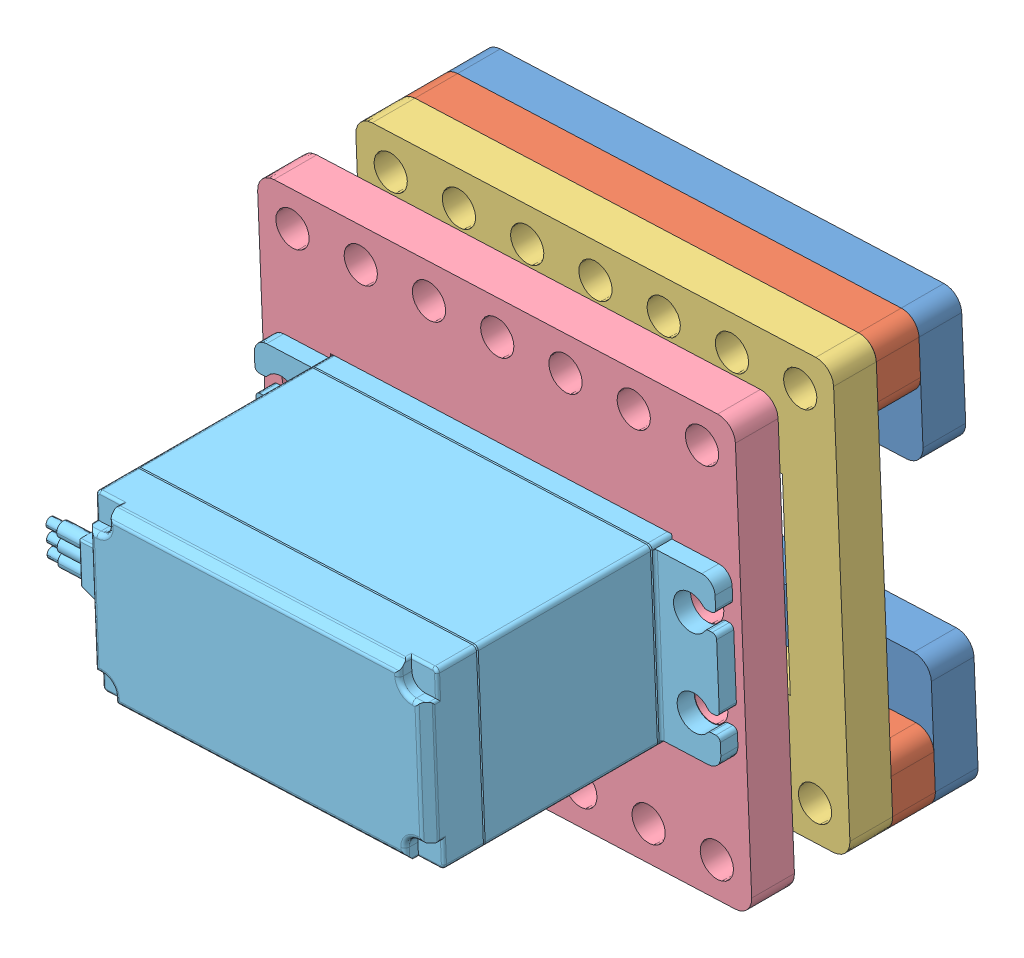
SolidWorks assembly assensceur fou9a, configuration Default. Lengths in mm.
Overall size (58.03 51.54 55.5).
10 component instances, 8 part files, 27 mates.
Components (placement in the parent):
- 3mm support servo 5-1: 3mm support servo 5 [Default] at (55.3297 16.1146 111.995) x (-0.99911 -0.042175 0) z (0.042175 -0.99911 0) size (56 5 15)
- support servo 2-1: support servo 2 [Default] at (111.2799 18.4764 116.995) x (-0.99911 -0.042175 0) z (0.042175 -0.99911 0) size (56 5 8)
- X7 support servo 3-1: X7 support servo 3 [Default] at (55.3297 16.1146 121.995) x (-0.99911 -0.042175 0) z (0.042175 -0.99911 0) size (56 5 49.22)
- support servo 4-1: support servo 4 [Default] at (35.4252 -33.9894 133.495) x (0.99911 0.042175 0) z (-0.042175 0.99911 0) size (56 5 49.22)
- MG995.step-1: MG995.step [Default] at (84.3427 -7.2923 162.495) x (-0.99911 -0.042175 0) z (0 0 -1) size (55.5 20 44.5)
- 3mm support servo 5-2: 3mm support servo 5 [Default] at (57.4056 -33.0616 106.995) x (-0.99911 -0.042175 0) z (-0.042175 0.99911 0) size (56 5 15)
- new attach-1: new attach [Default] at (74.3516 -7.7141 116.995) x (0.99087 -0.134821 0) z (0 0 1) size (21 21 5.5)
- NEW ATTACH V4-1: NEW ATTACH V4 [Default] at (74.3516 -7.7141 111.995) x (-0.134821 -0.99087 0) z (0 0 1) size (24.86 25 5)
- support servo 2-3: support servo 2 [Default] at (57.4056 -33.0616 116.995) x (0.99911 0.042175 0) z (-0.042175 0.99911 0) size (56 5 8)
- NEW HORN-1: NEW HORN [Default] at (84.3427 -7.2923 117.995) x (-0.99911 -0.042175 0) z (0 0 -1) size (9.55 9.02 10)
Mates (geometry in assembly coordinates):
- Concentric2: concentric anti-aligned: cylinder of support servo 4-1 through (60.575 -13.3001 133.495) axis (0 0 -1) radius 1.95; cylinder of MG995.step-1 through (60.575 -13.3001 133.495) axis (0 0 1) radius 2
- Coincident3: coincident anti-aligned: plane of support servo 4-1 through (131.3465 17.3217 133.495) normal (0 0 1); plane of MG995.step-1 through (84.3427 -7.2923 133.495) normal (0 0 -1)
- Concentric12: concentric aligned: cylinder of MG995.step-1 through (74.3516 -7.7141 122.995) axis (0 0 1) radius 2; cylinder of new attach-1 through (74.3516 -7.7141 117.995) axis (0 0 1) radius 2.75
- Coincident30: coincident anti-aligned: plane of MG995.step-1 through (74.3516 -7.7141 117.995) normal (0 0 -1); plane of new attach-1 through (74.3516 -7.7141 117.995) normal (0 0 1)
- Concentric13: concentric aligned: cylinder of new attach-1 through (74.3516 -7.7141 120.495) axis (0 0 -1) radius 1.6; cylinder of NEW ATTACH V4-1 through (74.3516 -7.7141 116.995) axis (0 0 -1) radius 1.6
- Coincident34: coincident anti-aligned: plane of new attach-1 through (74.3516 -7.7141 116.995) normal (0 0 -1); plane of NEW ATTACH V4-1 through (74.3516 -7.7141 116.995) normal (0 0 1)
- Concentric15: concentric: cylinder of new attach-1 through (82.0211 -6.2346 115.495) axis (0 0 1) radius 1; cylinder of new attach 2-1 through (82.0211 -6.2346 116.995) axis (0 0 -1) radius 1
- Coincident44: coincident aligned: plane of support servo 4-1 through (113.3558 -30.6998 138.495) normal (0.99911 0.042175 0); plane of support servo 2-3 through (113.2714 -28.7015 111.995) normal (0.99911 0.042175 0)
- Coincident45: coincident aligned: plane of support servo 2-1 through (111.3643 16.4782 111.995) normal (0.99911 0.042175 0); plane of support servo 4-1 through (113.3558 -30.6998 138.495) normal (0.99911 0.042175 0)
- Coincident46: coincident aligned: plane of support servo 2-1 through (111.3643 16.4782 111.995) normal (0.99911 0.042175 0); plane of support servo 3-1 through (111.3643 16.4782 116.995) normal (0.99911 0.042175 0)
- Coincident48: coincident anti-aligned: plane of support servo 2-1 through (57.581 10.2043 116.995) normal (0 0 1); plane of support servo 3-1 through (59.3194 -30.979 116.995) normal (0 0 -1)
- Coincident49: coincident aligned: plane of support servo 2-1 through (109.2817 18.3921 111.995) normal (-0.042175 0.99911 0); plane of support servo 3-1 through (109.2817 18.3921 116.995) normal (-0.042175 0.99911 0)
- Coincident50: coincident anti-aligned: plane of support servo 4-1 through (63.9388 1.855 133.495) normal (0.042175 -0.99911 0); plane of MG995.step-1 through (103.9032 3.5423 126.495) normal (-0.042175 0.99911 0)
- Coincident51: coincident anti-aligned: plane of 3mm support servo 5-1 through (57.8762 3.2106 111.995) normal (0 0 1); plane of support servo 2-1 through (57.581 10.2043 111.995) normal (0 0 -1)
- Coincident52: coincident aligned: plane of 3mm support servo 5-1 through (109.2817 18.3921 106.995) normal (-0.042175 0.99911 0); plane of support servo 2-1 through (109.2817 18.3921 111.995) normal (-0.042175 0.99911 0)
- Coincident53: coincident aligned: plane of 3mm support servo 5-1 through (55.4141 14.1164 106.995) normal (-0.99911 -0.042175 0); plane of support servo 2-1 through (55.4141 14.1164 111.995) normal (-0.99911 -0.042175 0)
- Coincident54: coincident anti-aligned: plane of 3mm support servo 5-2 through (58.8555 -19.9888 111.995) normal (0 0 1); plane of support servo 2-3 through (111.1045 -24.7895 111.995) normal (0 0 -1)
- Coincident55: coincident aligned: plane of 3mm support servo 5-2 through (111.3575 -30.7841 111.995) normal (0.042175 -0.99911 0); plane of support servo 2-3 through (59.4038 -32.9772 111.995) normal (0.042175 -0.99911 0)
- Coincident56: coincident aligned: plane of 3mm support servo 5-2 through (57.3212 -31.0633 111.995) normal (-0.99911 -0.042175 0); plane of support servo 2-3 through (57.3212 -31.0633 111.995) normal (-0.99911 -0.042175 0)
- Coincident57: coincident aligned: plane of NEW ATTACH V4-1 through (74.3516 -7.7141 111.995) normal (0 0 -1); plane of support servo 2-3 through (111.1045 -24.7895 111.995) normal (0 0 -1)
- Coincident58: coincident anti-aligned: plane of support servo 3-1 through (59.3194 -30.979 116.995) normal (0 0 -1); plane of support servo 2-3 through (111.1045 -24.7895 116.995) normal (0 0 1)
- Coincident59: coincident aligned: plane of support servo 3-1 through (111.3575 -30.7841 116.995) normal (0.042175 -0.99911 0); plane of support servo 2-3 through (59.4038 -32.9772 111.995) normal (0.042175 -0.99911 0)
- Coincident60: coincident aligned: plane of support servo 4-1 through (37.4234 -33.9051 128.495) normal (0.042175 -0.99911 0); plane of support servo 2-3 through (59.4038 -32.9772 111.995) normal (0.042175 -0.99911 0)
- InPlace1: in place: plane of MG995.step-1 through (74.3516 -7.7141 117.995) normal (0 0 -1); plane of ? through (0 0 117.995) normal (0 0 -1); moOrthogonalPlaneRef_w of MG995.step-1 through (74.3516 -7.7141 117.995) normal (0 0 -1); plane of ? through (0 0 117.995) normal (0 1 0); plane of MG995.step-1 through (74.3516 -7.7141 117.995) normal (0 0 -1); plane of ? through (0 0 117.995) normal (-1 0 0); plane of MG995.step-1 through (74.3516 -7.7141 117.995) normal (0 0 -1); unknown of NEW HORN-1
- Coincident61: coincident aligned: plane of ?; plane of ?
- Coincident62: coincident aligned: moOrthogonalPlaneRef_w of MG995.step-1 through (84.3427 -7.2923 117.995) normal (-0.042175 0.99911 0); plane of NEW HORN-1 through (84.3427 -7.2923 117.995) normal (-0.042175 0.99911 0)
- Coincident63: coincident anti-aligned: moOrthogonalPlaneRef_w of MG995.step-1 through (84.3427 -7.2923 117.995) normal (0.99911 0.042175 0); plane of NEW HORN-1 through (84.3427 -7.2923 117.995) normal (-0.99911 -0.042175 0)
